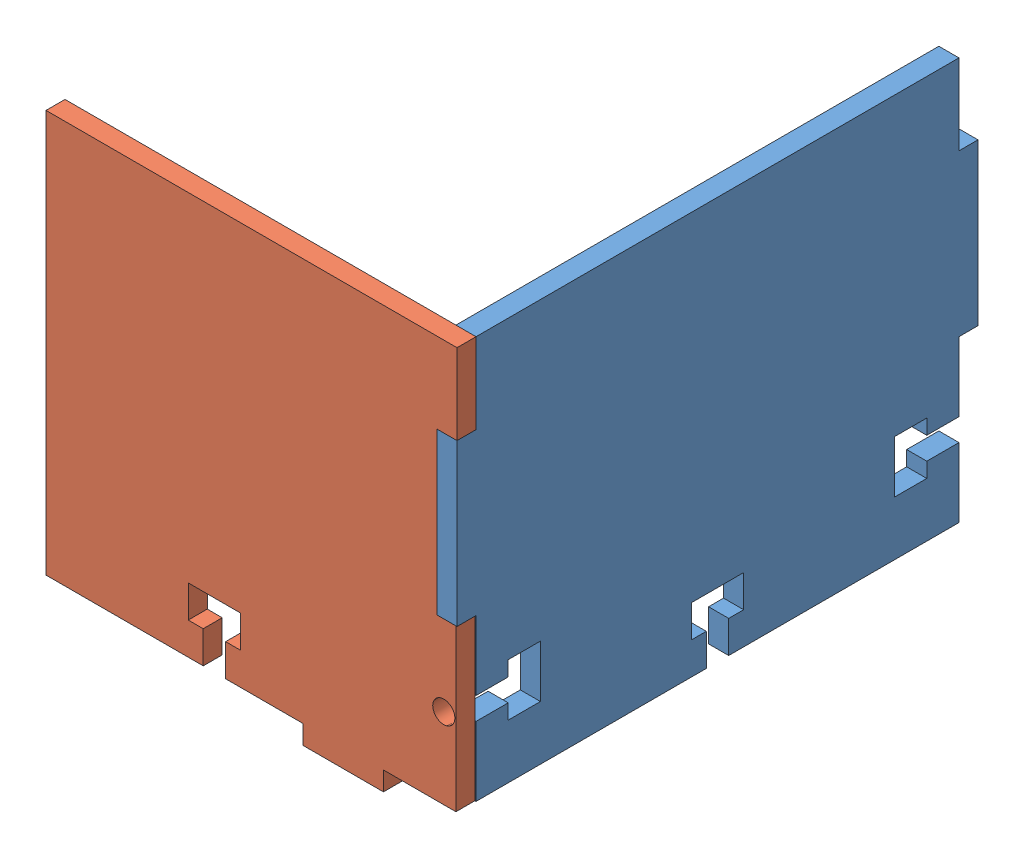
SolidWorks assembly planetest, configuration Default. Lengths in mm.
Overall size (64.85 66.5 82.2).
2 component instances, 2 part files, 3 mates.
Components (placement in the parent):
- plane_back-1: plane_back [Default] at (35.3127 44.7061 59.4231) size (3.17 63.5 82.2)
- test-1: test [Default] at (-75.9873 44.7061 97.5231) size (64.85 66.5 3)
Mates (geometry in assembly coordinates):
- Coincident1: coincident: plane of plane_back-1 through (38.4877 63.7561 100.5231) normal (0 0 1); plane of test-1 through (-75.9873 44.7061 100.5231) normal (0 0 1)
- Coincident2: coincident: plane of plane_back-1 through (38.4877 76.4561 97.5231) normal (0 1 0); plane of test-1 through (-26.3589 76.4561 100.5231) normal (0 1 0)
- Coincident3: coincident aligned: plane of plane_back-1 through (38.4877 44.7061 59.4231) normal (1 0 0); plane of test-1 through (38.4877 76.4561 100.5231) normal (1 0 0)
